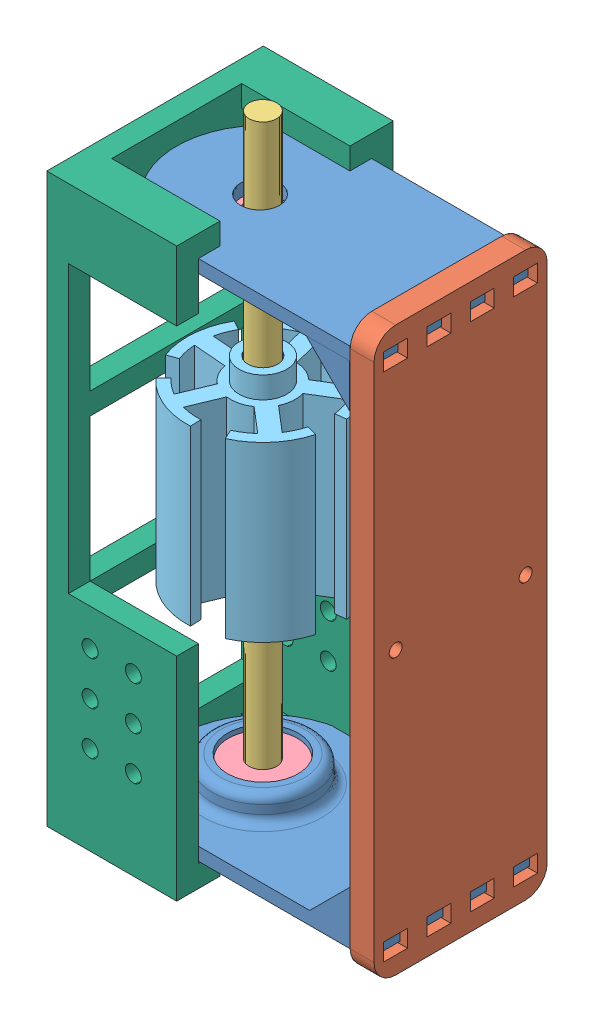
SolidWorks assembly test_jig_assembly, configuration Default. Lengths in mm.
Overall size (70.56 142.5 50).
8 component instances, 6 part files, 17 mates.
Components (placement in the parent):
- rotor_jig_top-1: rotor_jig_top [Default] at (-41.053 14.1044 37.4446) size (63.65 13 40)
- rotor_jig_top-2: rotor_jig_top [Default] at (-41.1986 135.1044 37.9446) x (1 0 0) z (0 0 -1) size (63.65 13 40)
- rotor_jig_base-2: rotor_jig_base [Default] at (-15.6404 74.6044 37.9446) x (0 -1 0) z (0 0 -1) size (130 5.5 40)
- test_shaft-1: test_shaft [Default] at (-61.7947 9.6044 37.4446) x (0.850837 0 0.525429) z (-0.525429 0 0.850837) size (6.38 142 6.38)
- test_bearing-1: test_bearing [Default] at (-61.7947 17.1044 37.4446) size (16 5 16)
- test_bearing-2: test_bearing [Default] at (-61.9403 127.1044 37.9446) size (16 5 16)
- 5pole_testrotor-1: 5pole_testrotor [Default] at (-61.7947 57.649 37.4446) x (-0.99909 0 0.042661) z (-0.042661 0 -0.99909) size (34.96 45 35)
- brush_jig_addon-1: brush_jig_addon [Default] at (-86.1986 74.6044 37.9446) x (0 1 0) z (0 0 -1) size (131 30 50)
Mates (geometry in assembly coordinates):
- Distance10: distance = 0.25 mm anti-aligned: plane of rotor_jig_base-2 through (-15.6404 135.6044 45.6946) normal (0 0 -1); plane of rotor_jig_top-2 through (-21.1792 132.1044 45.4446) normal (0 0 1)
- Distance11: distance = 0 mm anti-aligned: plane of rotor_jig_top-2 through (-21.1404 132.1044 20.4446) normal (1 0 0); plane of rotor_jig_base-2 through (-21.1404 74.6044 37.9446) normal (-1 0 0)
- Distance12: distance = 0.5 mm anti-aligned: plane of rotor_jig_base-2 through (-15.6404 131.6044 55.6946) normal (0 1 0); plane of rotor_jig_top-2 through (-61.1986 132.1044 37.9446) normal (0 -1 0)
- Distance15: distance = 0.25 mm anti-aligned: plane of rotor_jig_top-1 through (-21.053 17.1044 19.9446) normal (0 0 -1); plane of rotor_jig_base-2 through (-15.6404 13.6044 20.1946) normal (0 0 1)
- Distance16: distance = 0.5 mm anti-aligned: plane of rotor_jig_top-1 through (-61.053 17.1044 37.4446) normal (0 1 0); plane of rotor_jig_base-2 through (-15.6404 17.6044 25.6946) normal (0 -1 0)
- Distance17: distance = 0 mm anti-aligned: plane of rotor_jig_top-1 through (-21.1404 17.1044 17.4449) normal (1 0 0); plane of rotor_jig_base-2 through (-21.1404 74.6044 37.9446) normal (-1 0 0)
- Concentric1: concentric aligned: circle of rotor_jig_top-1; circle of test_shaft-1
- Distance18: distance = 0 mm anti-aligned: plane of test_bearing-2 through (-61.9403 132.1044 37.9446) normal (0 1 0); plane of rotor_jig_top-2 through (-61.1986 132.1044 37.9446) normal (0 -1 0)
- Concentric4: concentric anti-aligned: circle of rotor_jig_top-2; circle of test_bearing-2
- Distance19: distance = 0 mm anti-aligned: plane of rotor_jig_top-1 through (-61.053 17.1044 37.4446) normal (0 1 0); plane of test_bearing-1 through (-61.7947 17.1044 37.4446) normal (0 -1 0)
- Concentric5: concentric aligned: circle of rotor_jig_top-1; circle of test_bearing-1
- Concentric6: concentric aligned: circle of test_shaft-1; circle of 5pole_testrotor-1
- Lock3: lock: unknown of test_shaft-1; unknown of 5pole_testrotor-1
- Distance20: distance = 0 mm aligned: plane of test_shaft-1 through (-61.7947 9.6044 37.4446) normal (0 -1 0); plane of rotor_jig_base-2 through (-21.1404 9.6044 17.9446) normal (0 -1 0)
- Coincident4: coincident anti-aligned: plane of rotor_jig_top-2 through (-61.1986 135.1044 37.9446) normal (0 1 0); plane of brush_jig_addon-1 through (-56.1986 135.1044 37.9446) normal (0 -1 0)
- Coincident5: coincident anti-aligned: plane of rotor_jig_top-2 through (-61.1986 132.1044 17.9446) normal (0 0 -1); plane of brush_jig_addon-1 through (-81.1986 129.1044 17.9446) normal (0 0 1)
- Tangent2: tangent anti-aligned: cylinder of rotor_jig_top-2 through (-61.1986 132.1044 37.9446) axis (0 1 0) radius 20; plane of brush_jig_addon-1 through (-81.1986 74.6044 37.9446) normal (1 0 0)
